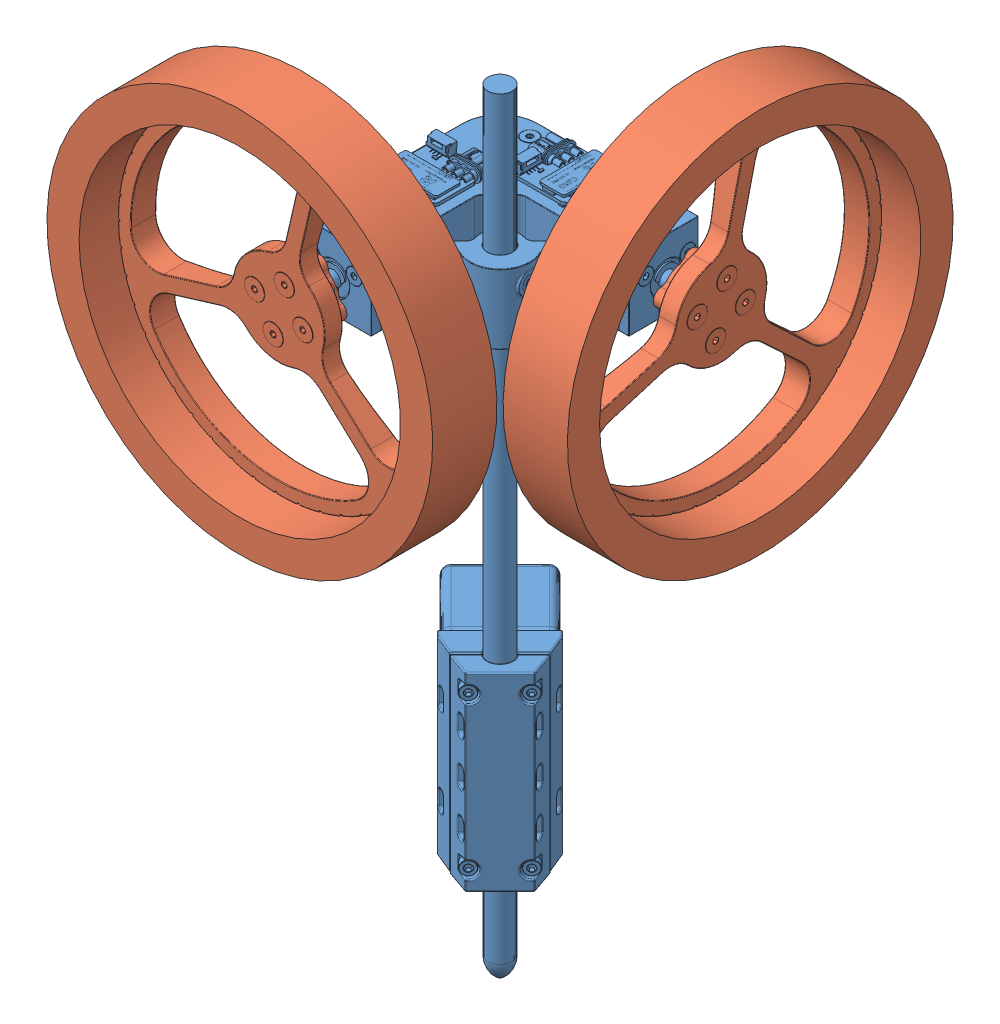
SolidWorks assembly Assem, configuration Default. Lengths in mm.
Overall size (181.63 313.62 181.24).
4 component instances, 3 part files, 7 mates.
Components (placement in the parent):
- BaseLink-1: BaseLink [Default] at (63.3663 182.9329 191.7647) size (92.92 304.8 92.92)
- Wheel-1: Wheel [Default] at (84.6904 239.1906 288.1937) x (0 0 1) z (-0.999388 -0.034977 0) size (31.93 152.4 152.4)
- Wheel-2: Wheel [Default] at (173.9064 239.1906 198.9717) x (1 0 0) z (0 -0.029714 0.999558) size (31.93 152.4 152.4)
- IMU Sensor-1: IMU Sensor [Default] at (80.9901 212.9387 200.0274) x (1 0 0) z (0 -1 0) size (2 13.5 8)
Mates (geometry in assembly coordinates):
- Concentric2: concentric aligned: cylinder of BaseLink-1 through (84.6874 239.1887 279.3864) axis (0 0 1) radius 3; cylinder of Wheel-1 through (84.6874 239.1887 279.3864) axis (0 0 1) radius 3
- Coincident1: coincident anti-aligned: plane of BaseLink-1 through (82.0894 240.6887 279.3864) normal (0 0 1); plane of Wheel-1 through (84.6874 239.1887 279.3864) normal (0 0 -1)
- Coincident2: coincident anti-aligned: plane of BaseLink-1 through (165.0991 240.6887 196.3767) normal (1 0 0); plane of Wheel-2 through (165.0991 239.1887 198.9747) normal (-1 0 0)
- Concentric3: concentric aligned: cylinder of BaseLink-1 through (165.0991 239.1887 198.9747) axis (1 0 0) radius 3; cylinder of Wheel-2 through (165.0991 239.1887 198.9747) axis (1 0 0) radius 3
- Coincident3: coincident anti-aligned: plane of BaseLink-1 through (80.9901 208.9387 193.2774) normal (1 0 0); plane of IMU Sensor-1 through (80.9901 212.9387 200.0274) normal (-1 0 0)
- Coincident4: coincident anti-aligned: plane of BaseLink-1 through (85.9901 216.9387 200.0274) normal (0 -1 0); plane of IMU Sensor-1 through (82.9901 216.9387 193.2774) normal (0 1 0)
- Coincident5: coincident aligned: plane of BaseLink-1 through (78.9901 208.9387 193.2774) normal (0 0 -1); plane of IMU Sensor-1 through (82.9901 208.9387 193.2774) normal (0 0 -1)
